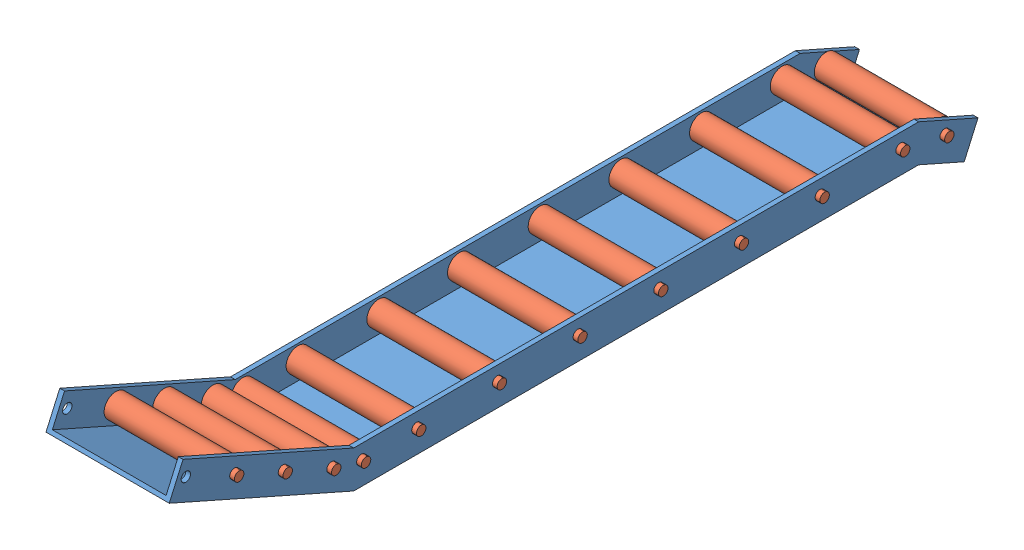
SolidWorks assembly Assembly-Scaled-Conveyor, configuration Default. Lengths in mm.
Overall size (140 339.39 853.06).
13 component instances, 2 part files, 50 mates.
Components (placement in the parent):
- Housing-Brace-1: Housing-Brace [Default] at (138.4638 -8.0875 9.7021) size (135 339.39 853.06)
- Roller-1: Roller [Default] at (8.4638 -8.0875 156.4026) x (0 0 -1) z (-1 0 0) size (25 25 140)
- Roller-3: Roller [Default] at (8.4638 -8.0875 -98.8974) x (0 0 -1) z (-1 0 0) size (25 25 140)
- Roller-4: Roller [Default] at (8.4638 -8.0875 -13.7974) x (0 -0.056104 -0.998425) z (-1 0 0) size (25 25 140)
- Roller-5: Roller [Default] at (8.4638 -8.0875 71.3026) x (0 0 -1) z (-1 0 0) size (25 25 140)
- Roller-6: Roller [Default] at (8.4638 -8.0875 -183.9974) x (0 0 -1) z (-1 0 0) size (25 25 140)
- Roller-7: Roller [Default] at (8.4638 -8.0875 -269.0974) x (0 0 -1) z (-1 0 0) size (25 25 140)
- Roller-8: Roller [Default] at (8.4638 -8.0875 241.5026) x (0 0.199031 -0.979993) z (-1 0 0) size (25 25 140)
- Roller-11: Roller [Default] at (8.4638 -18.3722 -315.5954) x (0 0.044275 -0.999019) z (-1 0 0) size (25 25 140)
- Roller-18: Roller [Default] at (8.4638 0.865 331.1112) x (0 0.044275 -0.999019) z (-1 0 0) size (25 25 140)
- Roller-19: Roller [Default] at (8.4638 -8.0875 299.6516) x (0 0.044275 -0.999019) z (-1 0 0) size (25 25 140)
- Roller-20: Roller [Default] at (8.4638 23.5172 382.3253) x (0 0.044275 -0.999019) z (-1 0 0) size (25 25 140)
- Roller-21: Roller [Default] at (8.4638 46.1694 433.5393) x (0 0.044275 -0.999019) z (-1 0 0) size (25 25 140)
Mates (geometry in assembly coordinates):
- Concentric1: concentric: cylinder of Housing-Brace-1 through (-871.5362 -8.0875 241.5026) axis (1 0 0) radius 5; cylinder of Roller-2 through (128.4638 -8.0875 265.0271) axis (-1 0 0) radius 5
- Coincident1: coincident anti-aligned: plane of Housing-Brace-1 through (128.4638 -8.0875 9.7021) normal (-1 0 0); plane of Roller-2 through (118.4638 -8.0875 265.0271) normal (1 0 0)
- Concentric2: concentric anti-aligned: cylinder of Housing-Brace-1 through (-871.5362 -8.0875 156.4026) axis (1 0 0) radius 5; cylinder of Roller-1 through (138.4638 -8.0875 156.4026) axis (-1 0 0) radius 5
- Concentric3: concentric anti-aligned: cylinder of Housing-Brace-1 through (-871.5362 -8.0875 71.3026) axis (1 0 0) radius 5; cylinder of Roller-5 through (138.4638 -8.0875 71.3026) axis (-1 0 0) radius 5
- Concentric4: concentric anti-aligned: cylinder of Housing-Brace-1 through (-871.5362 -8.0875 -13.7974) axis (1 0 0) radius 5; cylinder of Roller-4 through (138.4638 -8.0875 -13.7974) axis (-1 0 0) radius 5
- Concentric5: concentric anti-aligned: cylinder of Housing-Brace-1 through (-871.5362 -8.0875 -98.8974) axis (1 0 0) radius 5; cylinder of Roller-3 through (138.4638 -8.0875 -98.8974) axis (-1 0 0) radius 5
- Coincident2: coincident anti-aligned: plane of Housing-Brace-1 through (128.4638 -8.0875 9.7021) normal (-1 0 0); plane of Roller-1 through (128.4638 -8.0875 156.4026) normal (1 0 0)
- Coincident3: coincident anti-aligned: plane of Housing-Brace-1 through (128.4638 -8.0875 9.7021) normal (-1 0 0); plane of Roller-5 through (128.4638 -8.0875 71.3026) normal (1 0 0)
- Coincident4: coincident anti-aligned: plane of Housing-Brace-1 through (128.4638 -8.0875 9.7021) normal (-1 0 0); plane of Roller-4 through (128.4638 -8.0875 -13.7974) normal (1 0 0)
- Coincident5: coincident anti-aligned: plane of Housing-Brace-1 through (128.4638 -8.0875 9.7021) normal (-1 0 0); plane of Roller-3 through (128.4638 -8.0875 -98.8974) normal (1 0 0)
- Concentric6: concentric anti-aligned: cylinder of Housing-Brace-1 through (-871.5362 -8.0875 -183.9974) axis (1 0 0) radius 5; cylinder of Roller-6 through (138.4638 -8.0875 -183.9974) axis (-1 0 0) radius 5
- Concentric7: concentric anti-aligned: cylinder of Housing-Brace-1 through (-871.5362 -8.0875 -269.0974) axis (1 0 0) radius 5; cylinder of Roller-7 through (138.4638 -8.0875 -269.0974) axis (-1 0 0) radius 5
- Coincident6: coincident anti-aligned: plane of Housing-Brace-1 through (128.4638 -8.0875 9.7021) normal (-1 0 0); plane of Roller-7 through (128.4638 -8.0875 -269.0974) normal (1 0 0)
- Coincident7: coincident anti-aligned: plane of Housing-Brace-1 through (128.4638 -8.0875 9.7021) normal (-1 0 0); plane of Roller-6 through (128.4638 -8.0875 -183.9974) normal (1 0 0)
- Concentric8: concentric aligned: cylinder of Roller-7 through (128.4638 -8.0875 -269.0974) axis (-1 0 0) radius 12.5; cylinder of Conveyor-Belt-1 through (123.4638 -8.0875 -362.2579) axis (-1 0 0) radius 19.15
- Concentric9: concentric aligned: cylinder of Housing-Brace-1 through (-871.5362 -8.0875 241.5026) axis (1 0 0) radius 5; cylinder of Drive-Roller-1 through (-6.5362 -8.0875 262.2521) axis (1 0 0) radius 5
- Coincident9: coincident anti-aligned: plane of Housing-Brace-1 through (128.4638 -8.0875 9.7021) normal (-1 0 0); plane of Drive-Roller-1 through (128.4638 -8.0875 262.2521) normal (1 0 0)
- Distance2: distance = 5 mm anti-aligned: plane of Conveyor-Belt-1 through (123.4638 -8.0875 148.3421) normal (1 0 0); plane of Housing-Brace-1 through (128.4638 -8.0875 9.7021) normal (-1 0 0)
- Concentric10: concentric aligned: cylinder of Housing-Brace-1 through (-871.5362 -8.0875 241.5026) axis (1 0 0) radius 5; cylinder of Roller-8 through (-1.5362 -8.0875 241.5026) axis (1 0 0) radius 5
- Concentric11: concentric anti-aligned: cylinder of Housing-Brace-1 through (198.4638 0.865 331.1112) axis (-1 0 0) radius 5; cylinder of Roller-10 through (-6.5362 1.6769 334.954) axis (1 0 0) radius 5
- Concentric12: concentric anti-aligned: cylinder of Housing-Brace-1 through (198.4638 29.4823 411.4414) axis (-1 0 0) radius 5; cylinder of Roller-9 through (-6.5362 40.0118 505.12) axis (1 0 0) radius 5
- Concentric13: concentric: cylinder of Housing-Brace-1 through (198.4638 66.7877 487.9287) axis (-1 0 0) radius 5; cylinder of Roller-13 through (146.3825 77.3172 467.6974) axis (1 0 0) radius 5
- Concentric14: concentric anti-aligned: cylinder of Housing-Brace-1 through (198.4638 -18.3722 -315.5954) axis (-1 0 0) radius 5; cylinder of Roller-11 through (-1.5362 -18.3722 -315.5954) axis (1 0 0) radius 5
- Concentric15: concentric anti-aligned: cylinder of Housing-Brace-1 through (198.4638 -66.1311 -371.8133) axis (-1 0 0) radius 5; cylinder of Roller-12 through (-6.5362 -66.1311 -371.8133) axis (1 0 0) radius 5
- Concentric16: concentric anti-aligned: cylinder of Housing-Brace-1 through (198.4638 -103.4365 -448.3007) axis (-1 0 0) radius 5; cylinder of Roller-14 through (-6.5362 -103.4365 -448.3007) axis (1 0 0) radius 5
- Coincident11: coincident anti-aligned: plane of Housing-Brace-1 through (8.4638 -8.0875 9.7021) normal (1 0 0); plane of Roller-14 through (8.4638 -103.4365 -448.3007) normal (-1 0 0)
- Coincident12: coincident anti-aligned: plane of Housing-Brace-1 through (8.4638 -8.0875 9.7021) normal (1 0 0); plane of Roller-12 through (8.4638 -66.1311 -371.8133) normal (-1 0 0)
- Coincident13: coincident anti-aligned: plane of Housing-Brace-1 through (8.4638 -8.0875 9.7021) normal (1 0 0); plane of Roller-11 through (8.4638 -18.3722 -315.5954) normal (-1 0 0)
- Coincident18: coincident anti-aligned: plane of Housing-Brace-1 through (8.4638 -8.0875 9.7021) normal (1 0 0); plane of Roller-8 through (8.4638 -8.0875 241.5026) normal (-1 0 0)
- Coincident19: coincident anti-aligned: plane of Housing-Brace-1 through (8.4638 -8.0875 9.7021) normal (1 0 0); plane of Roller-10 through (8.4638 1.6769 334.954) normal (-1 0 0)
- Coincident20: coincident anti-aligned: plane of Housing-Brace-1 through (8.4638 -8.0875 9.7021) normal (1 0 0); plane of Roller-9 through (8.4638 40.0118 505.12) normal (-1 0 0)
- Coincident21: coincident anti-aligned: plane of Housing-Brace-1 through (8.4638 -8.0875 9.7021) normal (1 0 0); plane of Roller-13 through (8.4638 77.3172 467.6974) normal (-1 0 0)
- Concentric17: concentric: cylinder of Housing-Brace-1 through (198.4638 66.7877 487.9287) axis (-1 0 0) radius 5; cylinder of Drive-Roller-2 through (-6.5362 77.3172 467.6974) axis (1 0 0) radius 5
- Coincident22: coincident anti-aligned: plane of Housing-Brace-1 through (8.4638 -8.0875 9.7021) normal (1 0 0); plane of Drive-Roller-2 through (8.4638 77.3172 467.6974) normal (-1 0 0)
- Concentric18: concentric anti-aligned: cylinder of Housing-Brace-1 through (-871.5362 -8.0875 386.8493) axis (1 0 0) radius 5; cylinder of Roller-16 through (143.4638 -8.0875 386.8493) axis (-1 0 0) radius 5
- Concentric19: concentric anti-aligned: cylinder of Roller-17 through (143.4638 -8.0875 318.5421) axis (-1 0 0) radius 5; cylinder of Housing-Brace-1 through (-871.5362 -8.0875 318.5421) axis (1 0 0) radius 5
- Coincident23: coincident anti-aligned: plane of Housing-Brace-1 through (128.4638 -8.0875 9.7021) normal (-1 0 0); plane of Roller-17 through (128.4638 -8.0875 318.5421) normal (1 0 0)
- Concentric20: concentric anti-aligned: cylinder of Housing-Brace-1 through (-871.5362 -8.0875 233.4421) axis (1 0 0) radius 5; cylinder of Roller-15 through (143.4638 -8.0875 233.4421) axis (-1 0 0) radius 5
- Coincident24: coincident anti-aligned: plane of Housing-Brace-1 through (128.4638 -8.0875 9.7021) normal (-1 0 0); plane of Roller-15 through (128.4638 -8.0875 233.4421) normal (1 0 0)
- Coincident25: coincident anti-aligned: plane of Housing-Brace-1 through (128.4638 -8.0875 9.7021) normal (-1 0 0); plane of Roller-16 through (128.4638 -8.0875 386.8493) normal (1 0 0)
- Concentric21: concentric anti-aligned: cylinder of Housing-Brace-1 through (198.4638 29.4823 411.4414) axis (-1 0 0) radius 5; cylinder of Drive-Roller-3 through (-6.5362 29.4823 411.4414) axis (1 0 0) radius 5
- Coincident26: coincident anti-aligned: plane of Housing-Brace-1 through (8.4638 -8.0875 9.7021) normal (1 0 0); plane of Drive-Roller-3 through (8.4638 29.4823 411.4414) normal (-1 0 0)
- Concentric22: concentric aligned: cylinder of Housing-Brace-1 through (198.4638 0.865 331.1112) axis (-1 0 0) radius 5; cylinder of Roller-18 through (138.4638 0.865 331.1112) axis (-1 0 0) radius 5
- Coincident27: coincident anti-aligned: plane of Housing-Brace-1 through (128.4638 -8.0875 9.7021) normal (-1 0 0); plane of Roller-18 through (128.4638 0.865 331.1112) normal (1 0 0)
- Concentric25: concentric aligned: cylinder of Housing-Brace-1 through (-871.5362 -8.0875 299.6516) axis (1 0 0) radius 5; cylinder of Roller-19 through (-1.5362 -8.0875 299.6516) axis (1 0 0) radius 5
- Coincident30: coincident anti-aligned: plane of Housing-Brace-1 through (8.4638 -8.0875 9.7021) normal (1 0 0); plane of Roller-19 through (8.4638 -8.0875 299.6516) normal (-1 0 0)
- Concentric26: concentric anti-aligned: cylinder of Housing-Brace-1 through (198.4638 23.5172 382.3253) axis (-1 0 0) radius 5; cylinder of Roller-20 through (-1.5362 23.5172 382.3253) axis (1 0 0) radius 5
- Coincident31: coincident anti-aligned: plane of Housing-Brace-1 through (8.4638 -8.0875 9.7021) normal (1 0 0); plane of Roller-20 through (8.4638 23.5172 382.3253) normal (-1 0 0)
- Concentric27: concentric anti-aligned: cylinder of Housing-Brace-1 through (198.4638 46.1694 433.5393) axis (-1 0 0) radius 5; cylinder of Roller-21 through (-1.5362 46.1694 433.5393) axis (1 0 0) radius 5
- Coincident32: coincident anti-aligned: plane of Housing-Brace-1 through (8.4638 -8.0875 9.7021) normal (1 0 0); plane of Roller-21 through (8.4638 46.1694 433.5393) normal (-1 0 0)
